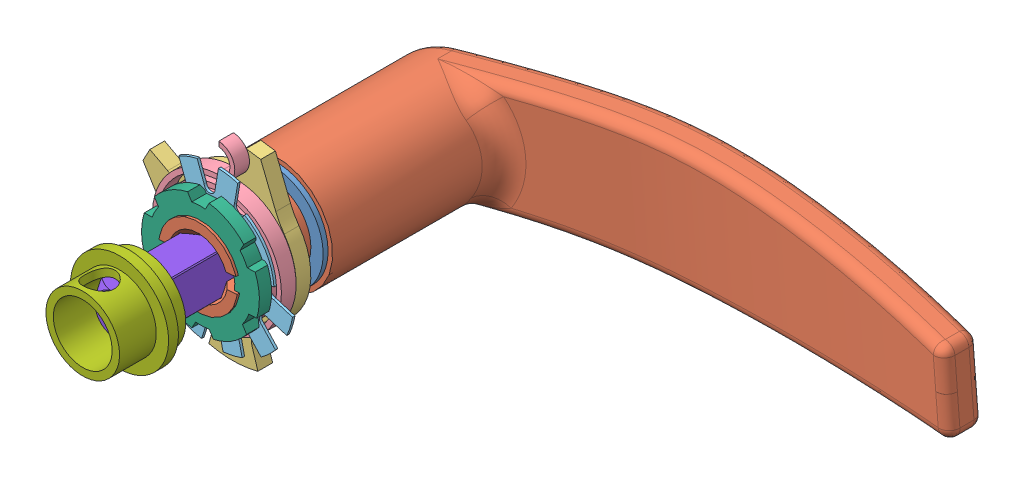
SolidWorks assembly poigne exterieure, configuration Défaut. Lengths in mm.
Overall size (128.25 51.13 93.38).
9 component instances, 8 part files, 16 mates.
Components (placement in the parent):
- pièce a3-1: pièce a3 [Défaut] at (-71.1604 -5.4234 -28.5) x (-1 0 0) z (0 0 -1) size (21 21 1)
- pièce a3-3: pièce a3 [Défaut] at (-71.1604 -5.4234 -33.5) x (0.888915 -0.458071 0) z (0 0 1) size (21 21 1)
- bequille-1: bequille [Défaut] at (-71.0971 -5.4183 -34) x (-0.081007 0.996714 0) z (0 0 1) size (41.55 120 69.88)
- pièce a16-1: pièce a16 [Défaut] at (-71.1604 -5.4234 -25) x (-0.999944 -0.010542 0) z (0 0 -1) size (31.16 38.76 3.06)
- pièce a5-1: pièce a5 [Défaut] at (-70.822 -5.1825 -23.5) x (-0.082996 -0.99655 0) z (0 0 -1) size (33.22 26.47 3.09)
- pièce a7-1: pièce a7 [Défaut] at (-71.1604 -5.4234 -21.5) x (-0.986222 0.165429 0) z (0 0 -1) size (28 32 0.5)
- pièce a4-1: pièce a4 [Défaut] at (-71.1604 -5.4234 -18.5) x (-0.884093 0.467311 0) z (0 0 -1) size (23.6 24 3)
- Pièce16-1: Pièce16 [Défaut] at (-71.1604 -5.4234 -7) x (0 0 1) z (0.996714 0.081007 0) size (12.5 20 20)
- carre-1: carre [Défaut] at (-71.1604 -5.4234 -53) x (-0.996714 -0.081007 0) z (0 0 -1) size (8 8 52)
Mates (geometry in assembly coordinates):
- Coïncidente331: coincident anti-aligned: plane of pièce a3-3 through (-71.1604 -5.4234 -34) normal (0 0 -1); plane of bequille-1 through (-71.1604 -5.4234 -34) normal (0 0 1)
- Coaxiale20: concentric anti-aligned: cylinder of pièce a16-1 through (-71.1604 -5.4234 -28) axis (0 0 1) radius 8; cylinder of bequille-1 through (-71.1604 -5.4234 -18) axis (0 0 -1) radius 8
- Tangent5: tangent: face of pièce a5-1; cylinder of bequille-1 through (-71.1604 -5.4234 -18) axis (0 0 -1) radius 8
- Coïncidente13: coincident anti-aligned: plane of pièce a16-1 through (-71.1604 -5.4234 -25) normal (0 0 1); plane of pièce a5-1 through (-63.1763 -5.8193 -25) normal (0 0 -1)
- Coïncidente50: coincident anti-aligned: plane of pièce a16-1 through (-71.1604 -5.4234 -25) normal (0 0 1); plane of pièce a5-1 through (-63.1763 -5.8193 -25) normal (0 0 -1)
- Coïncidente305: coincident anti-aligned: plane of pièce a4-1 through (-71.1604 -5.4234 -21.5) normal (0 0 -1); plane of pièce a7-1 through (-72.3014 6.4687 -21.5) normal (0 0 1)
- Coaxiale110: concentric anti-aligned: cylinder of pièce a7-1 through (-71.1604 -5.4234 -22) axis (0 0 1) radius 8; cylinder of bequille-1 through (-71.1604 -5.4234 -18) axis (0 0 -1) radius 8
- Coïncidente303: coincident anti-aligned: plane of pièce a7-1 through (-79.1142 -4.5649 -22) normal (-0.081007 0.996714 0); plane of bequille-1 through (-91.2161 -5.5485 -30) normal (0.081007 -0.996714 0)
- Coïncidente302: coincident anti-aligned: plane of pièce a5-1 through (-62.1797 -5.9023 -22) normal (0 0 1); plane of pièce a7-1 through (-72.3014 6.4687 -22) normal (0 0 -1)
- Coaxiale103: concentric aligned: cylinder of pièce a4-1 through (-71.1604 -5.4234 -21.5) axis (0 0 -1) radius 7; cylinder of bequille-1 through (-71.1604 -5.4234 -18) axis (0 0 -1) radius 8
- Coïncidente332: coincident anti-aligned: plane of bequille-1 through (-74.8232 -9.7343 -53) normal (0.996714 0.081007 0); plane of carre-1 through (-75.4712 -1.7606 -1) normal (-0.996714 -0.081007 0)
- Coïncidente333: coincident anti-aligned: plane of bequille-1 through (-75.4712 -1.7606 -53) normal (0.081007 -0.996714 0); plane of carre-1 through (-67.4975 -1.1126 -1) normal (-0.081007 0.996714 0)
- Coïncidente334: coincident anti-aligned: plane of bequille-1 through (-74.8232 -9.7343 -53) normal (0 0 1); plane of carre-1 through (-66.8495 -9.0863 -53) normal (0 0 -1)
- Coïncidente339: coincident anti-aligned: plane of Pièce16-1 through (-75.4712 -1.7606 5.5) normal (0.081007 -0.996714 0); plane of carre-1 through (-67.4975 -1.1126 -1) normal (-0.081007 0.996714 0)
- Coïncidente340: coincident anti-aligned: plane of Pièce16-1 through (-74.8232 -9.7343 5.5) normal (0.996714 0.081007 0); plane of carre-1 through (-75.4712 -1.7606 -1) normal (-0.996714 -0.081007 0)
- Coïncidente341: coincident aligned: plane of Pièce16-1 through (-71.1604 -5.4234 -7) normal (0 0 -1); plane of carre-1 through (-71.1604 -5.4234 -7) normal (0 0 -1)
